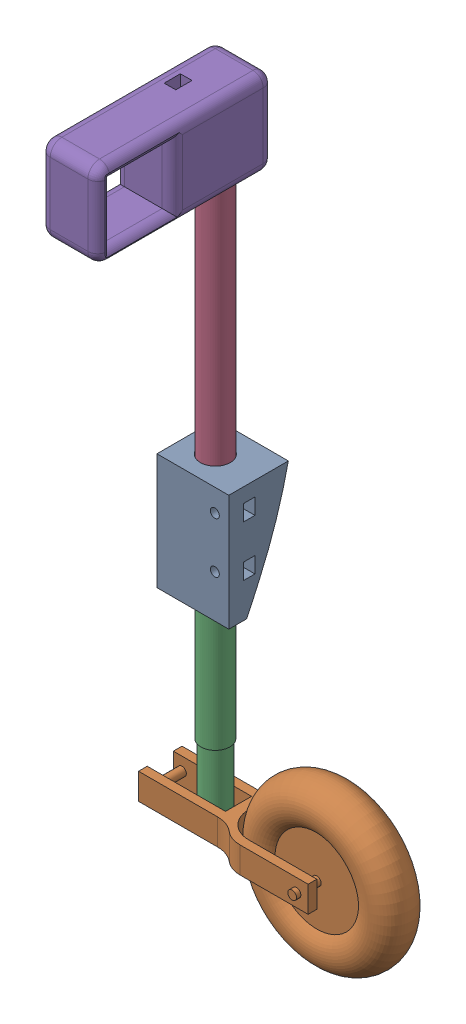
SolidWorks assembly Mirrorright rear gear, configuration Default. Lengths in mm.
Overall size (86.5 247.1 63.95).
5 component instances, 5 part files, 11 mates.
Components (placement in the parent):
- Mirrorrear gear part 1-1: Mirrorrear gear part 1 [Default] at (22.7002 5.5024 -14.7192) size (24.8 40 20.53)
- Mirrorwheel-1: Mirrorwheel [Default] at (16.0502 -63.9976 -24.7192) x (0 0 1) z (0 -1 0) size (27 86.5 55)
- Mirrorlanding gear main rod-1: Mirrorlanding gear main rod [Default] at (8.0502 25.5024 -24.7192) x (-1 0 0) z (0 0 1) size (10 90 10)
- Mirrorcarbon fiber support-1: Mirrorcarbon fiber support [Default] at (8.0502 150.5024 -24.7192) x (-0.837169 0 0.546944) z (0.546944 0 0.837169) size (10 120 10)
- Mirrormain support of rear gear-1: Mirrormain support of rear gear [Default] at (18.0502 134.5024 20.7308) x (0 0 -1) z (0 1 0) size (60.45 20 29.6)
Mates (geometry in assembly coordinates):
- Concentric1: concentric anti-aligned: cylinder of Mirrorwheel-1 through (8.0502 -59.4976 -36.4618) axis (0 0 1) radius 1.5; cylinder of Mirrorlanding gear main rod-1 through (8.0502 -59.4976 7.7808) axis (0 0 -1) radius 1.5
- Parallel1: parallel anti-aligned: plane of Mirrorwheel-1 through (16.2721 -54.9976 -42.2192) normal (0 1 0); plane of Mirrorlanding gear main rod-1 through (8.0502 -64.4976 -24.7192) normal (0 -1 0)
- Width1: width: line of Mirrorwheel-1; plane of Mirrorwheel-1 through (-10.9498 -54.9976 -17.2192) normal (0 0 1); axis of Mirrorlanding gear main rod-1 through (8.0502 -64.4976 -24.7192) axis (0 1 0)
- Concentric2: concentric anti-aligned: cylinder of Mirrorrear gear part 1-1 through (8.0502 25.5024 -24.7192) axis (0 -1 0) radius 5.15; cylinder of Mirrorlanding gear main rod-1 through (8.0502 -39.4976 -24.7192) axis (0 1 0) radius 5
- Perpendicular1: perpendicular: plane of Mirrorrear gear part 1-1 through (-2.0998 45.5024 -14.7192) normal (-1 0 0); plane of Mirrorwheel-1 through (52.0502 -54.9976 -36.7192) normal (0 0 -1)
- Coincident1: coincident anti-aligned: plane of Mirrorrear gear part 1-1 through (8.0502 25.5024 -24.7192) normal (0 -1 0); plane of Mirrorlanding gear main rod-1 through (8.0502 25.5024 -24.7192) normal (0 1 0)
- Coincident2: coincident anti-aligned: plane of Mirrorrear gear part 1-1 through (8.0502 30.5024 -24.7192) normal (0 1 0); plane of Mirrorcarbon fiber support-1 through (8.0502 30.5024 -24.7192) normal (0 -1 0)
- Concentric3: concentric anti-aligned: cylinder of Mirrorrear gear part 1-1 through (8.0502 50.5024 -24.7192) axis (0 -1 0) radius 5.15; cylinder of Mirrorcarbon fiber support-1 through (8.0502 30.5024 -24.7192) axis (0 1 0) radius 5
- Coincident3: coincident anti-aligned: plane of Mirrorcarbon fiber support-1 through (8.0502 150.5024 -24.7192) normal (0 1 0); plane of Mirrormain support of rear gear-1 through (18.0502 150.5024 20.7308) normal (0 -1 0)
- Concentric4: concentric anti-aligned: cylinder of Mirrorcarbon fiber support-1 through (8.0502 30.5024 -24.7192) axis (0 1 0) radius 5; cylinder of Mirrormain support of rear gear-1 through (8.0502 150.5024 -24.7192) axis (0 -1 0) radius 5.15
- Parallel2: parallel aligned: plane of Mirrorrear gear part 1-1 through (22.7002 45.5024 -14.7192) normal (0 0 1); plane of Mirrormain support of rear gear-1 through (-1.9498 134.5024 25.7308) normal (0 0 1)
